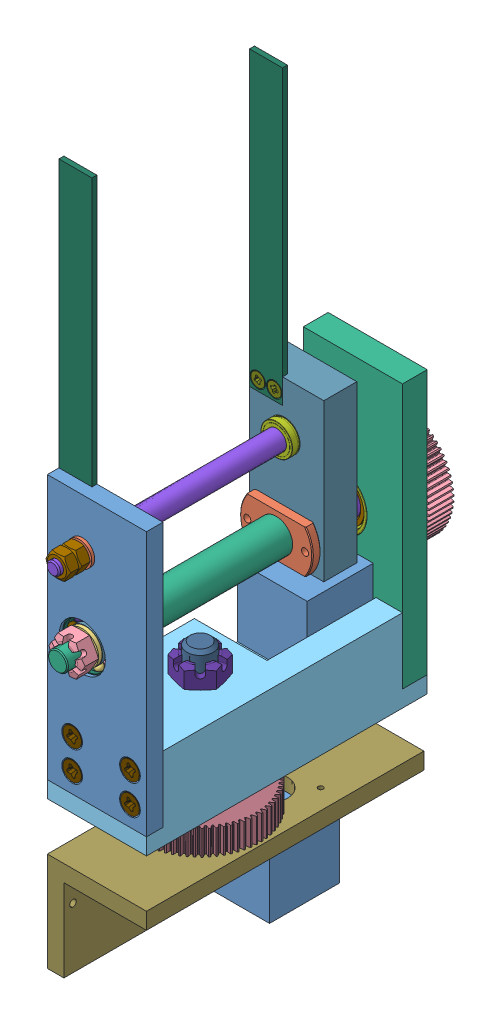
SolidWorks assembly Greifer, configuration Standard. Lengths in mm.
Overall size (102.7 421 224).
72 component instances, 42 part files, 88 mates.
Components (placement in the parent):
- Halterung_statisch-1: Halterung_statisch [Standard] at origin size (60 160 10)
- Spannscheibe_Achse-2: Spannscheibe_Achse [Standard] at (21.15 130 11.8) x (1 0 0) z (0 1 0) size (15 1.8 15)
- Spannscheibe_Welle-1: Spannscheibe_Welle [Standard] at (21.15 80 10.2) x (-0.964763 -0.263119 0) z (0 0 -1) size (20 20 2.2)
- mutter_din_937-m12-kk-14h_-_au-1: mutter_din_937-m12-kk-14h_-_au [Default] at (21.15 80 10.2) size (21.94 19 10)
- Haltearm_Drehgelenk2-1: Haltearm_Drehgelenk2 [Standard] at (65 -10 -158) x (0 0 1) z (-1 0 0) size (170 50 60)
- Halterung_Motor-2: Halterung_Motor [Standard] at (65 0 -145) x (-1 0 0) z (0 0 -1) size (60 160 15)
- Spannscheibe_Achse-3: Spannscheibe_Achse [Standard] at (21.15 130 -160) x (-0.971616 -0.236562 0) z (0.236562 -0.971616 0) size (15 1.8 15)
- inafag_n202-e-tvp2_aqqhrrap8qdp81ymy9u0uz87v-1: inafag_n202-e-tvp2_aqqhrrap8qdp81ymy9u0uz87v [Default] at (21.15 80 -145) x (0 0 -1) z (0.94526 -0.326318 0) size (11 35 35)
  - inafag_n202-e-tvp2_aqqhrrap8qdp81ymy9u0uz87v_01-1: inafag_n202-e-tvp2_aqqhrrap8qdp81ymy9u0uz87v_01 [Default] at origin size (11 35 35)
  - inafag_n202-e-tvp2_aqqhrrap8qdp81ymy9u0uz87v_02-1: inafag_n202-e-tvp2_aqqhrrap8qdp81ymy9u0uz87v_02 [Default] at origin size (11 21.6 21.6)
  - inafag_n202-e-tvp2_aqqhrrap8qdp81ymy9u0uz87v_03-1: inafag_n202-e-tvp2_aqqhrrap8qdp81ymy9u0uz87v_03 [Default] at origin size (7.58 28.12 28.12)
  - inafag_n202-e-tvp2_aqqhrrap8qdp81ymy9u0uz87v_04-1: inafag_n202-e-tvp2_aqqhrrap8qdp81ymy9u0uz87v_04 [Default] at origin size (5.3 5.5 5.5)
  - inafag_n202-e-tvp2_aqqhrrap8qdp81ymy9u0uz87v_05-1: inafag_n202-e-tvp2_aqqhrrap8qdp81ymy9u0uz87v_05 [Default] at origin size (5.3 5.5 5.5)
  - inafag_n202-e-tvp2_aqqhrrap8qdp81ymy9u0uz87v_06-1: inafag_n202-e-tvp2_aqqhrrap8qdp81ymy9u0uz87v_06 [Default] at origin size (5.3 5.5 5.5)
  - inafag_n202-e-tvp2_aqqhrrap8qdp81ymy9u0uz87v_07-1: inafag_n202-e-tvp2_aqqhrrap8qdp81ymy9u0uz87v_07 [Default] at origin size (5.3 5.5 5.5)
- Führungsarm-1: Führungsarm [Standard] at (43 65 -112.3939) x (-1 0 0) z (0 0 -1) size (45 95 20)
- Greifarm-2: Greifarm [Standard] at (0 322 -115.3939) x (0 -1 0) z (0 0 1) size (177 20 3)
- Greifarm-3: Greifarm [Standard] at (20 322 3) x (0 -1 0) z (0 0 -1) size (177 20 3)
- din_en_iso_7046-2_m4x8_h_1-1: din_en_iso_7046-2_m4x8_h_1 [Default] at (15 151 0) size (8.4 8.4 8)
- din_en_iso_7046-2_m4x8_h_1-2: din_en_iso_7046-2_m4x8_h_1 [Default] at (5 151 0) size (8.4 8.4 8)
- din_en_iso_7046-2_m4x8_h_1-3: din_en_iso_7046-2_m4x8_h_1 [Default] at (5 151 -112.3939) x (-0.923728 -0.383049 0) z (0 0 -1) size (8.4 8.4 8)
- din_en_iso_7046-2_m4x8_h_1-4: din_en_iso_7046-2_m4x8_h_1 [Default] at (15 151 -112.3939) x (-0.228703 -0.973496 0) z (0 0 -1) size (8.4 8.4 8)
- mutter_din_937-m16-kk-14h_-_au-4: mutter_din_937-m16-kk-14h_-_au [Default] at (32.5 40.9141 -50) x (-0.96716 0 -0.254167) z (0 1 0) size (27.71 24 12)
- Spannscheibe_Welle-2: Spannscheibe_Welle [Standard] at (21.15 80 -183.2) size (20 20 2.2)
- mutter_din_937-m12-kk-14h_-_au-2: mutter_din_937-m12-kk-14h_-_au [Default] at (21.15 80 -183.2) x (0.661925 -0.74957 0) z (0 0 -1) size (21.94 19 10)
- din_en_iso_7046-2_m6x25_h_1-1: din_en_iso_7046-2_m6x25_h_1 [Default] at (15 30 10) x (-0.923728 -0.383049 0) z (0 0 -1) size (11.3 11.3 25)
- din_en_iso_7046-2_m6x25_h_1-2: din_en_iso_7046-2_m6x25_h_1 [Default] at (50 30 10) x (-0.923728 -0.383049 0) z (0 0 -1) size (11.3 11.3 25)
- din_en_iso_7046-2_m6x25_h_1-3: din_en_iso_7046-2_m6x25_h_1 [Default] at (15 12 10) x (-0.923728 -0.383049 0) z (0 0 -1) size (11.3 11.3 25)
- din_en_iso_7046-2_m6x25_h_1-4: din_en_iso_7046-2_m6x25_h_1 [Default] at (50 12 10) x (-0.923728 -0.383049 0) z (0 0 -1) size (11.3 11.3 25)
- Schrittmotor-4: Schrittmotor [Standard] at (42.3 57.15 -145) x (-1 0 0) z (0 0 1) size (42.3 42.3 64.5)
- mtspnr20_2_14b-1: mtspnr20_2_14b [Standard] at (21.15 80 -107.3939) x (0 0 -1) z (0 1 0) size (32 44 26.8)
- Halterung Zahnrrad-1: Halterung Zahnrrad [Standard] at (21.15 36 -149) x (0 0 -1) z (-0.155042 0.987908 0) size (32 18 18)
- 416-010-0066-1: 416-010-0066 [Standard] at (21.15 80 -173.5) x (0.298929 0.954275 0) z (0 0 1) size (68 67.96 25)
- 416-010-0022-2: 416-010-0022 [Standard] at (21.15 36 -173.5) x (0.612566 0.79042 0) z (0 0 1) size (24 23.84 23)
- Welle_bestellt-1: Welle_bestellt [Standard] at (21.15 80 25) x (0 0 -1) z (-0.896181 -0.443689 0) size (221 20 20)
- lmk12_2_14b-1: lmk12_2_14b [Standard] at (21.15 130 -122.5939) x (0 0 1) z (0.200949 -0.979602 0) size (30 19 19)
- Achse_neu-1: Achse_neu [Standard] at (21.15 130 0) x (0 0 -1) z (-0.921454 0.388487 0) size (204 12 12)
- mutter_din_en_24032-m8-6-1: mutter_din_en_24032-m8-6 [Default] at (21.15 130 -168.6) size (15.01 13 6.8)
- mutter_din_en_24032-m8-6-2: mutter_din_en_24032-m8-6 [Default] at (21.15 130 -175.4) size (15.01 13 6.8)
- mutter_din_en_24032-m8-6-3: mutter_din_en_24032-m8-6 [Default] at (21.15 130 11.8) size (15.01 13 6.8)
- mutter_din_en_24032-m8-6-4: mutter_din_en_24032-m8-6 [Default] at (21.15 130 18.6) size (15.01 13 6.8)
- Welle_drehgelenk_neu-2: Welle_drehgelenk_neu [Standard] at (39.0435 59 -45.3975) x (0 1 0) z (-0.575311 0 0.817935) size (127 20 20)
- 416-010-0014-1: 416-010-0014 [Standard] at (32.5009 -21.5 -92) x (0.923788 0 0.382905) z (0 -1 0) size (16 15.7 25)
- Motorhalterung-2: Motorhalterung [Standard] at (0 -49 -158) x (0 0 1) z (0 1 0) size (168 60 60)
- 416-010-0070-1: 416-010-0070 [Standard] at (32.5 -21.5 -50) x (-0.880097 0 0.474795) z (0 -1 0) size (72 71.96 25)
- Schrittmotor-5: Schrittmotor [Standard] at (11.3509 -49 -113.15) x (1 0 0) z (0 -1 0) size (42.3 42.3 64.5)
- inafag_16002_9gwbvro1p7ifqmz6650knblzl-1: inafag_16002_9gwbvro1p7ifqmz6650knblzl [Default] at (21.15 80 0) x (0 0 1) z (-1 0 0) size (8 32 32)
  - inafag_16002_9gwbvro1p7ifqmz6650knblzl_01-1: inafag_16002_9gwbvro1p7ifqmz6650knblzl_01 [Default] at origin size (8 20.45 20.45)
  - inafag_16002_9gwbvro1p7ifqmz6650knblzl_02-1: inafag_16002_9gwbvro1p7ifqmz6650knblzl_02 [Default] at origin size (8 32 32)
  - inafag_16002_9gwbvro1p7ifqmz6650knblzl_03-1: inafag_16002_9gwbvro1p7ifqmz6650knblzl_03 [Default] at origin size (6.69 6.17 6.63)
  - inafag_16002_9gwbvro1p7ifqmz6650knblzl_04-1: inafag_16002_9gwbvro1p7ifqmz6650knblzl_04 [Default] at origin size (6.69 6.17 6.63)
  - inafag_16002_9gwbvro1p7ifqmz6650knblzl_05-1: inafag_16002_9gwbvro1p7ifqmz6650knblzl_05 [Default] at origin size (6.69 6.17 6.63)
  - inafag_16002_9gwbvro1p7ifqmz6650knblzl_06-1: inafag_16002_9gwbvro1p7ifqmz6650knblzl_06 [Default] at origin size (6.69 6.17 6.63)
  - inafag_16002_9gwbvro1p7ifqmz6650knblzl_07-1: inafag_16002_9gwbvro1p7ifqmz6650knblzl_07 [Default] at origin size (6.69 6.17 6.63)
  - inafag_16002_9gwbvro1p7ifqmz6650knblzl_08-1: inafag_16002_9gwbvro1p7ifqmz6650knblzl_08 [Default] at origin size (6.69 6.17 6.63)
  - inafag_16002_9gwbvro1p7ifqmz6650knblzl_09-1: inafag_16002_9gwbvro1p7ifqmz6650knblzl_09 [Default] at origin size (6.69 6.17 6.63)
  - inafag_16002_9gwbvro1p7ifqmz6650knblzl_10-1: inafag_16002_9gwbvro1p7ifqmz6650knblzl_10 [Default] at origin size (6.69 6.17 6.63)
  - inafag_16002_9gwbvro1p7ifqmz6650knblzl_11-1: inafag_16002_9gwbvro1p7ifqmz6650knblzl_11 [Default] at origin size (6.52 5.76 5.81)
- inafag_16002_9gwbvro1p7ifqmz6650knblzl-2: inafag_16002_9gwbvro1p7ifqmz6650knblzl [Default] at (32.5 -39 -50) x (0 -1 0) z (0 0 1) size (8 32 32)
  - inafag_16002_9gwbvro1p7ifqmz6650knblzl_01-1: inafag_16002_9gwbvro1p7ifqmz6650knblzl_01 [Default] at origin size (8 20.45 20.45)
  - inafag_16002_9gwbvro1p7ifqmz6650knblzl_02-1: inafag_16002_9gwbvro1p7ifqmz6650knblzl_02 [Default] at origin size (8 32 32)
  - inafag_16002_9gwbvro1p7ifqmz6650knblzl_03-1: inafag_16002_9gwbvro1p7ifqmz6650knblzl_03 [Default] at origin size (6.69 6.17 6.63)
  - inafag_16002_9gwbvro1p7ifqmz6650knblzl_04-1: inafag_16002_9gwbvro1p7ifqmz6650knblzl_04 [Default] at origin size (6.69 6.17 6.63)
  - inafag_16002_9gwbvro1p7ifqmz6650knblzl_05-1: inafag_16002_9gwbvro1p7ifqmz6650knblzl_05 [Default] at origin size (6.69 6.17 6.63)
  - inafag_16002_9gwbvro1p7ifqmz6650knblzl_06-1: inafag_16002_9gwbvro1p7ifqmz6650knblzl_06 [Default] at origin size (6.69 6.17 6.63)
  - inafag_16002_9gwbvro1p7ifqmz6650knblzl_07-1: inafag_16002_9gwbvro1p7ifqmz6650knblzl_07 [Default] at origin size (6.69 6.17 6.63)
  - inafag_16002_9gwbvro1p7ifqmz6650knblzl_08-1: inafag_16002_9gwbvro1p7ifqmz6650knblzl_08 [Default] at origin size (6.69 6.17 6.63)
  - inafag_16002_9gwbvro1p7ifqmz6650knblzl_09-1: inafag_16002_9gwbvro1p7ifqmz6650knblzl_09 [Default] at origin size (6.69 6.17 6.63)
  - inafag_16002_9gwbvro1p7ifqmz6650knblzl_10-1: inafag_16002_9gwbvro1p7ifqmz6650knblzl_10 [Default] at origin size (6.69 6.17 6.63)
  - inafag_16002_9gwbvro1p7ifqmz6650knblzl_11-1: inafag_16002_9gwbvro1p7ifqmz6650knblzl_11 [Default] at origin size (6.52 5.76 5.81)
- Spannscheibe_Welle-3: Spannscheibe_Welle [Standard] at (32.5 -49.2 -50) x (1 0 0) z (0 1 0) size (20 20 2.2)
- mutter_din_937-m12-kk-14h_-_au-3: mutter_din_937-m12-kk-14h_-_au [Default] at (32.5 -49.2 -50) x (-0.991519 0 0.129964) z (0 -1 0) size (21.94 19 10)
Mates (geometry in assembly coordinates):
- Deckungsgleich10: coincident anti-aligned: plane of Halterung_statisch-1 through (0 0 10) normal (0 0 1); plane of Spannscheibe_Achse-2 through (21.15 130 10) normal (0 0 -1)
- Deckungsgleich13: coincident anti-aligned: plane of Spannscheibe_Welle-1 through (21.15 80 10.2) normal (0 0 1); plane of mutter_din_937-m12-kk-14h_-_au-1 through (32.1197 80 10.2) normal (0 0 -1)
- Deckungsgleich14: coincident anti-aligned: plane of Halterung_statisch-1 through (0 0 0) normal (0 0 -1); plane of Haltearm_Drehgelenk2-1 through (0 0 0) normal (0 0 1)
- Deckungsgleich15: coincident anti-aligned: plane of Halterung_statisch-1 through (0 0 10) normal (0 -1 0); plane of Haltearm_Drehgelenk2-1 through (0 0 10) normal (0 1 0)
- Deckungsgleich24: coincident anti-aligned: plane of Haltearm_Drehgelenk2-1 through (0 40 -145) normal (0 0 -1); plane of Halterung_Motor-2 through (65 0 -145) normal (0 0 1)
- Deckungsgleich26: coincident anti-aligned: plane of Haltearm_Drehgelenk2-1 through (0 0 -145) normal (0 1 0); plane of Halterung_Motor-2 through (65 0 -160) normal (0 -1 0)
- Deckungsgleich27: coincident aligned: plane of Haltearm_Drehgelenk2-1 through (0 -10 -158) normal (-1 0 0); plane of Halterung_Motor-2 through (0 0 -160) normal (-1 0 0)
- Deckungsgleich28: coincident anti-aligned: plane of Halterung_Motor-2 through (65 0 -160) normal (0 0 -1); plane of Spannscheibe_Achse-3 through (21.15 130 -160) normal (0 0 1)
- Deckungsgleich30: coincident anti-aligned: plane of Halterung_Motor-2 through (21.15 80 -156) normal (0 0 1); plane of inafag_n202-e-tvp2_aqqhrrap8qdp81ymy9u0uz87v-1/inafag_n202-e-tvp2_aqqhrrap8qdp81ymy9u0uz87v_01-1 through (36.5143 74.696 -156) normal (0 0 -1)
- Deckungsgleich33: coincident anti-aligned: plane of Führungsarm-1 through (0 145 -115.3939) normal (0 0 1); plane of Greifarm-2 through (0 322 -115.3939) normal (0 0 -1)
- Deckungsgleich34: coincident anti-aligned: plane of Führungsarm-1 through (43 145 -112.3939) normal (0 1 0); plane of Greifarm-2 through (0 145 -112.3939) normal (0 -1 0)
- Deckungsgleich35: coincident aligned: plane of Greifarm-2 through (0 322 -112.3939) normal (-1 0 0); plane of Führungsarm-1 through (0 65 -132.3939) normal (-1 0 0)
- Deckungsgleich44: coincident anti-aligned: plane of Halterung_statisch-1 through (0 145 0) normal (0 1 0); plane of Greifarm-3 through (20 145 0) normal (0 -1 0)
- Deckungsgleich45: coincident anti-aligned: plane of Halterung_statisch-1 through (0 145 3) normal (0 0 -1); plane of Greifarm-3 through (20 322 3) normal (0 0 1)
- Deckungsgleich46: coincident aligned: plane of Halterung_statisch-1 through (0 0 10) normal (-1 0 0); plane of Greifarm-3 through (0 322 0) normal (-1 0 0)
- Deckungsgleich47: coincident anti-aligned: plane of Halterung_statisch-1 through (15 151 8) normal (0 0 -1); plane of din_en_iso_7046-2_m4x8_h_1-1 through (15 151 8) normal (0 0 1)
- Konzentrisch22: concentric aligned: cylinder of Halterung_statisch-1 through (15 151 8) axis (0 0 -1) radius 1.62; cylinder of din_en_iso_7046-2_m4x8_h_1-1 through (15 151 0) axis (0 0 -1) radius 2
- Deckungsgleich48: coincident anti-aligned: plane of Halterung_statisch-1 through (5 151 8) normal (0 0 -1); plane of din_en_iso_7046-2_m4x8_h_1-2 through (5 151 8) normal (0 0 1)
- Konzentrisch23: concentric aligned: cylinder of Halterung_statisch-1 through (5 151 8) axis (0 0 -1) radius 1.62; cylinder of din_en_iso_7046-2_m4x8_h_1-2 through (5 151 0) axis (0 0 -1) radius 2
- Deckungsgleich49: coincident anti-aligned: plane of Führungsarm-1 through (5 151 -120.3939) normal (0 0 1); plane of din_en_iso_7046-2_m4x8_h_1-3 through (5 151 -120.3939) normal (0 0 -1)
- Konzentrisch24: concentric anti-aligned: cone of Greifarm-2 through (5 151 -115.0939) axis (0 0 -1); cylinder of din_en_iso_7046-2_m4x8_h_1-3 through (5 151 -112.3939) axis (0 0 1) radius 2
- Deckungsgleich50: coincident anti-aligned: plane of Führungsarm-1 through (15 151 -120.3939) normal (0 0 1); plane of din_en_iso_7046-2_m4x8_h_1-4 through (15 151 -120.3939) normal (0 0 -1)
- Konzentrisch25: concentric aligned: cylinder of Führungsarm-1 through (15 151 -120.3939) axis (0 0 1) radius 1.62; cylinder of din_en_iso_7046-2_m4x8_h_1-4 through (15 151 -112.3939) axis (0 0 1) radius 2
- Deckungsgleich63: coincident anti-aligned: plane of Spannscheibe_Welle-2 through (21.15 80 -183.2) normal (0 0 -1); plane of mutter_din_937-m12-kk-14h_-_au-2 through (28.4111 71.7775 -183.2) normal (0 0 1)
- Deckungsgleich64: coincident anti-aligned: plane of Haltearm_Drehgelenk2-1 through (15 30 -15) normal (0 0 1); plane of din_en_iso_7046-2_m6x25_h_1-1 through (15 30 -15) normal (0 0 -1)
- Konzentrisch32: concentric aligned: cylinder of Haltearm_Drehgelenk2-1 through (15 30 -15) axis (0 0 1) radius 2.5; cylinder of din_en_iso_7046-2_m6x25_h_1-1 through (15 30 10) axis (0 0 1) radius 3
- Deckungsgleich65: coincident anti-aligned: plane of Haltearm_Drehgelenk2-1 through (50 30 -15) normal (0 0 1); plane of din_en_iso_7046-2_m6x25_h_1-2 through (50 30 -15) normal (0 0 -1)
- Konzentrisch33: concentric aligned: cylinder of Halterung_statisch-1 through (50 30 -15) axis (0 0 1) radius 3; cylinder of din_en_iso_7046-2_m6x25_h_1-2 through (50 30 10) axis (0 0 1) radius 3
- Deckungsgleich66: coincident anti-aligned: plane of Haltearm_Drehgelenk2-1 through (15 12 -15) normal (0 0 1); plane of din_en_iso_7046-2_m6x25_h_1-3 through (15 12 -15) normal (0 0 -1)
- Konzentrisch34: concentric aligned: cylinder of Halterung_statisch-1 through (15 12 -22) axis (0 0 1) radius 3; cylinder of din_en_iso_7046-2_m6x25_h_1-3 through (15 12 10) axis (0 0 1) radius 3
- Deckungsgleich67: coincident anti-aligned: plane of Haltearm_Drehgelenk2-1 through (50 12 -15) normal (0 0 1); plane of din_en_iso_7046-2_m6x25_h_1-4 through (50 12 -15) normal (0 0 -1)
- Konzentrisch35: concentric aligned: cylinder of Halterung_statisch-1 through (50 12 -22) axis (0 0 1) radius 3; cylinder of din_en_iso_7046-2_m6x25_h_1-4 through (50 12 10) axis (0 0 1) radius 3
- Deckungsgleich79: coincident aligned: plane of Haltearm_Drehgelenk2-1 through (0 -10 -158) normal (-1 0 0); plane of Schrittmotor-4 through (0 57.15 -105) normal (-1 0 0)
- Deckungsgleich80: coincident anti-aligned: plane of Haltearm_Drehgelenk2-1 through (-55 14.85 -145) normal (0 1 0); plane of Schrittmotor-4 through (42.3 14.85 -105) normal (0 -1 0)
- Deckungsgleich81: coincident anti-aligned: plane of Halterung_Motor-2 through (65 0 -145) normal (0 0 1); plane of Schrittmotor-4 through (42.3 57.15 -145) normal (0 0 -1)
- Parallel1: parallel aligned: plane of Führungsarm-1 through (43 65 -132.3939) normal (0 -1 0); plane of mtspnr20_2_14b-1 through (43.15 67 -107.3939) normal (0 -1 0)
- Deckungsgleich88: coincident anti-aligned: plane of Führungsarm-1 through (43 65 -112.3939) normal (0 0 1); plane of mtspnr20_2_14b-1 through (3.7 80 -112.3939) normal (0 0 -1)
- Konzentrisch49: concentric aligned: cylinder of Führungsarm-1 through (21.15 80 -98.3939) axis (0 0 -1) radius 13; cylinder of mtspnr20_2_14b-1 through (21.15 80 -125.8439) axis (0 0 -1) radius 13
- Deckungsgleich95: coincident anti-aligned: plane of inafag_n202-e-tvp2_aqqhrrap8qdp81ymy9u0uz87v-1/inafag_n202-e-tvp2_aqqhrrap8qdp81ymy9u0uz87v_02-1 through (29.7991 77.0142 -156) normal (0 0 -1); plane of 416-010-0066-1 through (21.15 80 -156) normal (0 0 1)
- Konzentrisch57: concentric aligned: cylinder of mtspnr20_2_14b-1 through (21.15 80 -123.3939) axis (0 0 -1) radius 8; cylinder of Welle_bestellt-1 through (21.15 80 -72.5) axis (0 0 -1) radius 10
- Deckungsgleich98: coincident anti-aligned: plane of Spannscheibe_Welle-1 through (21.15 80 8) normal (0 0 -1); plane of Welle_bestellt-1 through (22.8138 76.6393 8) normal (0 0 1)
- Konzentrisch59: concentric aligned: cylinder of 416-010-0066-1 through (21.15 80 -181) axis (0 0 -1) radius 6; cylinder of Welle_bestellt-1 through (21.15 80 -175.95) axis (0 0 -1) radius 6
- Deckungsgleich100: coincident anti-aligned: plane of Schrittmotor-4 through (21.15 36 -169.5) normal (0 0 -1); plane of Halterung Zahnrrad-1 through (21.15 36 -169.5) normal (0 0 1)
- Deckungsgleich101: coincident anti-aligned: plane of Halterung Zahnrrad-1 through (22.0803 30.0726 -158) normal (0 0 -1); plane of 416-010-0022-2 through (21.15 36 -158) normal (0 0 1)
- Konzentrisch60: concentric aligned: cylinder of Halterung Zahnrrad-1 through (21.15 36 -149) axis (0 0 1) radius 6; cylinder of 416-010-0022-2 through (21.15 36 -196) axis (0 0 1) radius 6
- Konzentrisch61: concentric aligned: cylinder of Schrittmotor-4 through (21.15 36 -169.5) axis (0 0 1) radius 2.5; cylinder of Halterung Zahnrrad-1 through (21.15 36 -169.5) axis (0 0 1) radius 2.5
- Deckungsgleich102: coincident anti-aligned: plane of Spannscheibe_Welle-2 through (21.15 80 -181) normal (0 0 1); plane of 416-010-0066-1 through (21.15 80 -181) normal (0 0 -1)
- Konzentrisch62: concentric aligned: cylinder of Spannscheibe_Welle-2 through (21.15 80 -181) axis (0 0 -1) radius 6.5; cylinder of Welle_bestellt-1 through (21.15 80 -175.95) axis (0 0 -1) radius 6
- Konzentrisch63: concentric aligned: cylinder of mutter_din_937-m12-kk-14h_-_au-2 through (21.15 80 -193.2) axis (0 0 -1) radius 5.1881; cylinder of Welle_bestellt-1 through (21.15 80 -175.95) axis (0 0 -1) radius 6
- Konzentrisch65: concentric anti-aligned: cylinder of Führungsarm-1 through (21.15 130 -98.3939) axis (0 0 -1) radius 9.5; cylinder of lmk12_2_14b-1 through (21.15 130 -122.5939) axis (0 0 1) radius 9.5
- Deckungsgleich103: coincident aligned: plane of Führungsarm-1 through (43 65 -112.3939) normal (0 0 1); plane of lmk12_2_14b-1 through (12.0887 128.1412 -112.3939) normal (0 0 1)
- Deckungsgleich104: coincident anti-aligned: plane of Halterung_Motor-2 through (65 0 -145) normal (0 0 1); plane of Achse_neu-1 through (19.2658 125.5309 -145) normal (0 0 -1)
- Konzentrisch67: concentric anti-aligned: cylinder of lmk12_2_14b-1 through (21.15 130 -122.5939) axis (0 0 1) radius 6; cylinder of Achse_neu-1 through (21.15 130 -72.5) axis (0 0 -1) radius 6
- Konzentrisch68: concentric anti-aligned: cylinder of Achse_neu-1 through (21.15 130 -160.2165) axis (0 0 -1) radius 4; cylinder of mutter_din_en_24032-m8-6-1 through (21.15 130 -161.8) axis (0 0 1) radius 3.3234
- Deckungsgleich105: coincident anti-aligned: plane of Spannscheibe_Achse-3 through (21.15 130 -161.8) normal (0 0 -1); plane of mutter_din_en_24032-m8-6-1 through (28.6556 130 -161.8) normal (0 0 1)
- Konzentrisch69: concentric anti-aligned: cylinder of Achse_neu-1 through (21.15 130 -160.2165) axis (0 0 -1) radius 4; cylinder of mutter_din_en_24032-m8-6-2 through (21.15 130 -168.6) axis (0 0 1) radius 3.3234
- Deckungsgleich106: coincident anti-aligned: plane of mutter_din_en_24032-m8-6-1 through (28.6556 130 -168.6) normal (0 0 -1); plane of mutter_din_en_24032-m8-6-2 through (28.6556 130 -168.6) normal (0 0 1)
- Deckungsgleich107: coincident anti-aligned: plane of Spannscheibe_Achse-2 through (21.15 130 11.8) normal (0 0 1); plane of mutter_din_en_24032-m8-6-3 through (28.6556 130 11.8) normal (0 0 -1)
- Konzentrisch70: concentric anti-aligned: cylinder of Achse_neu-1 through (21.15 130 13.7165) axis (0 0 -1) radius 4; cylinder of mutter_din_en_24032-m8-6-3 through (21.15 130 18.6) axis (0 0 1) radius 3.3234
- Deckungsgleich108: coincident anti-aligned: plane of mutter_din_en_24032-m8-6-3 through (28.6556 130 18.6) normal (0 0 1); plane of mutter_din_en_24032-m8-6-4 through (28.6556 130 18.6) normal (0 0 -1)
- Konzentrisch72: concentric anti-aligned: cylinder of Achse_neu-1 through (21.15 130 13.7165) axis (0 0 -1) radius 4; cylinder of mutter_din_en_24032-m8-6-4 through (21.15 130 25.4) axis (0 0 1) radius 3.3234
- Konzentrisch73: concentric anti-aligned: cylinder of Spannscheibe_Achse-2 through (21.15 130 10) axis (0 0 1) radius 4.2; cylinder of Achse_neu-1 through (21.15 130 13.7165) axis (0 0 -1) radius 4
- Konzentrisch77: concentric anti-aligned: cylinder of Spannscheibe_Achse-3 through (21.15 130 -161.8) axis (0 0 1) radius 4.2; cylinder of Achse_neu-1 through (21.15 130 -160.2165) axis (0 0 -1) radius 4
- Konzentrisch82: concentric aligned: cylinder of Halterung_Motor-2 through (21.15 130 -125) axis (0 0 -1) radius 4; cylinder of Achse_neu-1 through (21.15 130 -160.2165) axis (0 0 -1) radius 4
- Konzentrisch86: concentric aligned: cylinder of inafag_n202-e-tvp2_aqqhrrap8qdp81ymy9u0uz87v-1/inafag_n202-e-tvp2_aqqhrrap8qdp81ymy9u0uz87v_02-1 through (21.15 80 -145) axis (0 0 -1) radius 7.5; cylinder of Welle_bestellt-1 through (21.15 80 -150.65) axis (0 0 -1) radius 7.5
- Konzentrisch87: concentric anti-aligned: cylinder of Halterung_Motor-2 through (21.15 80 -156) axis (0 0 1) radius 17.5; cylinder of inafag_n202-e-tvp2_aqqhrrap8qdp81ymy9u0uz87v-1/inafag_n202-e-tvp2_aqqhrrap8qdp81ymy9u0uz87v_01-1 through (21.15 80 -150.5) axis (0 0 -1) radius 17.5
- Konzentrisch91: concentric aligned: cylinder of Haltearm_Drehgelenk2-1 through (32.5 75 -50) axis (0 -1 0) radius 8; cylinder of Welle_drehgelenk_neu-2 through (32.5 -68 -50) axis (0 -1 0) radius 8
- Deckungsgleich114: coincident anti-aligned: plane of Haltearm_Drehgelenk2-1 through (0 -10 -158) normal (0 -1 0); plane of Welle_drehgelenk_neu-2 through (39.0435 -10 -45.3975) normal (0 1 0)
- Konzentrisch92: concentric anti-aligned: cylinder of mutter_din_937-m16-kk-14h_-_au-4 through (32.5 52.9141 -50) axis (0 1 0) radius 6.9175; cylinder of Welle_drehgelenk_neu-2 through (32.5 -68 -50) axis (0 -1 0) radius 8
- Deckungsgleich120: coincident aligned: plane of Haltearm_Drehgelenk2-1 through (0 -10 10) normal (0 0 1); plane of Motorhalterung-2 through (60 -39 10) normal (0 0 1)
- Konzentrisch102: concentric aligned: cylinder of Welle_drehgelenk_neu-2 through (32.5 -68 -50) axis (0 -1 0) radius 7.5; cylinder of 416-010-0070-1 through (32.5 15 -50) axis (0 -1 0) radius 7.5
- Deckungsgleich125: coincident anti-aligned: plane of Welle_drehgelenk_neu-2 through (40.6793 -14 -44.2469) normal (0 -1 0); plane of 416-010-0070-1 through (32.5 -14 -50) normal (0 1 0)
- Deckungsgleich127: coincident anti-aligned: plane of Motorhalterung-2 through (0 -49 -158) normal (0 -1 0); plane of Schrittmotor-5 through (11.3509 -49 -113.15) normal (0 1 0)
- Konzentrisch103: concentric aligned: cylinder of Motorhalterung-2 through (32.5009 -27.4 -92) axis (0 -1 0) radius 11; cylinder of Schrittmotor-5 through (32.5009 -47 -92) axis (0 -1 0) radius 11
- Konzentrisch104: concentric anti-aligned: cylinder of 416-010-0014-1 through (32.5009 -14 -92) axis (0 1 0) radius 2.5; cylinder of Schrittmotor-5 through (32.5009 -24.5 -92) axis (0 -1 0) radius 2.5
- Konzentrisch105: concentric anti-aligned: cylinder of Welle_bestellt-1 through (21.15 80 4.15) axis (0 0 -1) radius 7.5; cylinder of inafag_16002_9gwbvro1p7ifqmz6650knblzl-1/inafag_16002_9gwbvro1p7ifqmz6650knblzl_01-1 through (21.15 80 0.3) axis (0 0 1) radius 7.5
- Deckungsgleich128: coincident anti-aligned: plane of Welle_bestellt-1 through (23.3684 75.5191 0) normal (0 0 1); plane of inafag_16002_9gwbvro1p7ifqmz6650knblzl-1/inafag_16002_9gwbvro1p7ifqmz6650knblzl_01-1 through (12.1375 80 0) normal (0 0 -1)
- Deckungsgleich129: coincident anti-aligned: plane of Motorhalterung-2 through (32.5 -47 -50) normal (0 1 0); plane of inafag_16002_9gwbvro1p7ifqmz6650knblzl-2/inafag_16002_9gwbvro1p7ifqmz6650knblzl_02-1 through (32.5 -47 -35.435) normal (0 -1 0)
- Konzentrisch106: concentric anti-aligned: cylinder of Motorhalterung-2 through (32.5 -47 -50) axis (0 1 0) radius 16; cylinder of inafag_16002_9gwbvro1p7ifqmz6650knblzl-2/inafag_16002_9gwbvro1p7ifqmz6650knblzl_02-1 through (32.5 -43 -50) axis (0 -1 0) radius 16
- Konzentrisch107: concentric aligned: cylinder of Welle_drehgelenk_neu-2 through (32.5 -68 -50) axis (0 -1 0) radius 7.5; cylinder of inafag_16002_9gwbvro1p7ifqmz6650knblzl-2/inafag_16002_9gwbvro1p7ifqmz6650knblzl_01-1 through (32.5 -39.3 -50) axis (0 -1 0) radius 7.5
- Deckungsgleich130: coincident anti-aligned: plane of 416-010-0070-1 through (32.5 -39 -50) normal (0 -1 0); plane of inafag_16002_9gwbvro1p7ifqmz6650knblzl-2/inafag_16002_9gwbvro1p7ifqmz6650knblzl_01-1 through (32.5 -39 -40.9875) normal (0 1 0)
- Abstand5: distance = 8 mm anti-aligned: plane of Schrittmotor-5 through (32.5009 -47 -92) normal (0 1 0); plane of 416-010-0014-1 through (32.5009 -39 -92) normal (0 -1 0)
- Parallel2: parallel anti-aligned: plane of Motorhalterung-2 through (10 -99 -158) normal (1 0 0); plane of Schrittmotor-5 through (11.3509 -89 -113.15) normal (-1 0 0)
- Deckungsgleich133: coincident anti-aligned: plane of Welle_drehgelenk_neu-2 through (32.5 -47 -50) normal (0 -1 0); plane of Spannscheibe_Welle-3 through (32.5 -47 -50) normal (0 1 0)
- Konzentrisch108: concentric aligned: cylinder of Welle_drehgelenk_neu-2 through (32.5 -47 -50) axis (0 -1 0) radius 6; cylinder of Spannscheibe_Welle-3 through (32.5 -47 -50) axis (0 -1 0) radius 6.5
- Konzentrisch109: concentric aligned: cylinder of Welle_drehgelenk_neu-2 through (32.5 -47 -50) axis (0 -1 0) radius 6; cylinder of mutter_din_937-m12-kk-14h_-_au-3 through (32.5 -59.2 -50) axis (0 -1 0) radius 5.1881
- Deckungsgleich134: coincident anti-aligned: plane of Spannscheibe_Welle-3 through (32.5 -49.2 -50) normal (0 -1 0); plane of mutter_din_937-m12-kk-14h_-_au-3 through (21.6234 -49.2 -48.5743) normal (0 1 0)
- Deckungsgleich135: coincident aligned: plane of Halterung_statisch-1 through (0 0 10) normal (-1 0 0); plane of Haltearm_Drehgelenk2-1 through (0 -10 -158) normal (-1 0 0)
